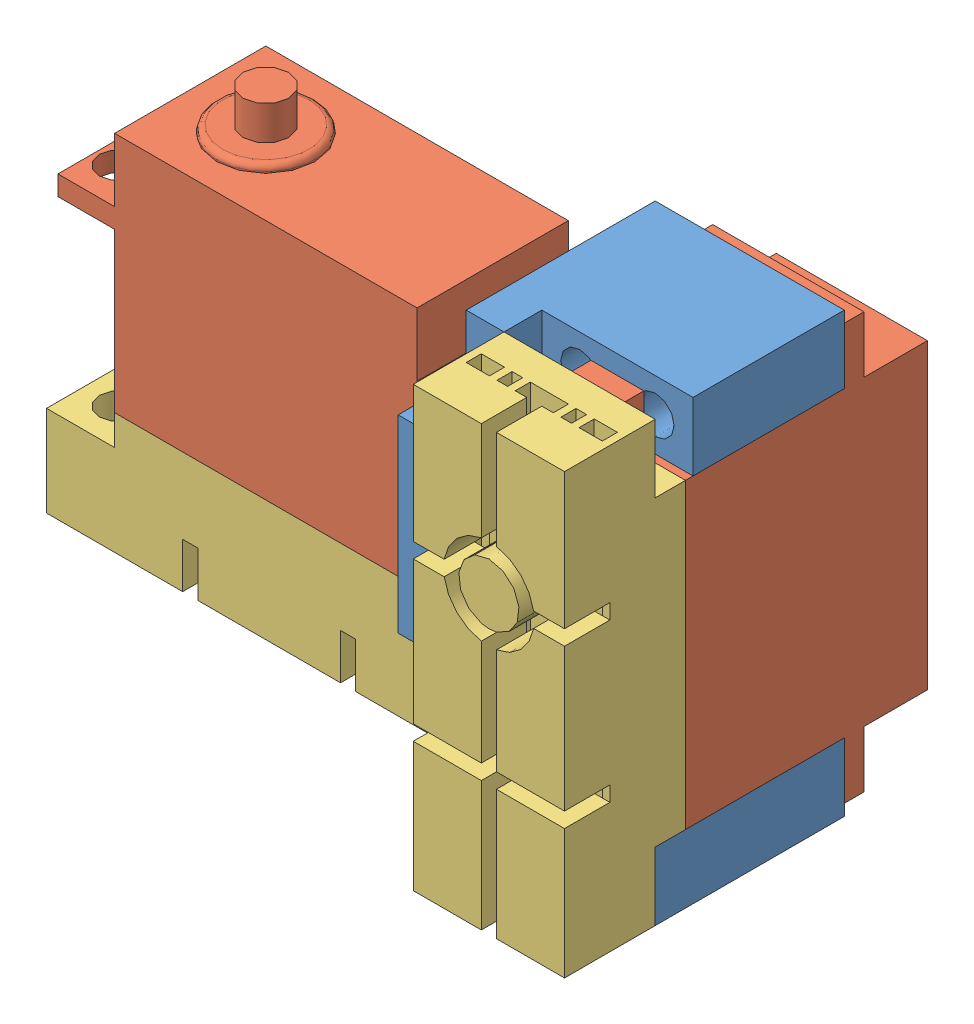
SolidWorks assembly Pate, configuration Défaut. Lengths in mm.
Overall size (83 58 53.5).
5 component instances, 3 part files, 14 mates.
Components (placement in the parent):
- shoulder-1: shoulder [Défaut] at origin size (34 58 25)
- Servo_TGY1501_body-1: Servo_TGY1501_body [Défaut] at (0 -8.5 12.5) x (-1 0 0) z (0 0 -1) size (55 41 20)
- base_servo-1: base_servo [Défaut] at (-49 -12.5 2.5) x (1 0 0) z (0 -1 0) size (58 20 16)
- Servo_TGY1501_body-2: Servo_TGY1501_body [Défaut] at (24 -20 21) x (0 1 0) z (-1 0 0) size (55 41 20)
- base_servo-2: base_servo [Défaut] at (14 29 25) x (0 -1 0) z (0 0 1) size (58 20 16)
Mates (geometry in assembly coordinates):
- Parallèle1: parallel anti-aligned: plane of Servo_TGY1501_body-1 through (0 -8.5 2.5) normal (0 -1 0); plane of base_servo-1 through (-49 -12.5 2.5) normal (0 1 0)
- Coaxiale1: concentric anti-aligned: cylinder of Servo_TGY1501_body-1; cylinder of base_servo-1
- Coaxiale2: concentric aligned: cylinder of Servo_TGY1501_body-1; cylinder of base_servo-1
- Coïncidente2: coincident anti-aligned: plane of Servo_TGY1501_body-1 through (0 -8.5 2.5) normal (0 -1 0); plane of base_servo-1 through (0 -8.5 2.5) normal (0 1 0)
- Coïncidente3: coincident anti-aligned: plane of shoulder-1 through (0 12.5 25) normal (0 1 0); plane of Servo_TGY1501_body-1 through (-40 12.5 30.4379) normal (0 -1 0)
- Coaxiale3: concentric aligned: cylinder of shoulder-1; cylinder of Servo_TGY1501_body-1
- Coaxiale4: concentric anti-aligned: cylinder of shoulder-1; cylinder of base_servo-1
- Parallèle2: parallel anti-aligned: plane of Servo_TGY1501_body-2 through (14 -20 21) normal (0 0 1); plane of base_servo-2 through (14 29 25) normal (0 0 -1)
- Coïncidente5: coincident aligned: plane of Servo_TGY1501_body-2 through (34 -20 21) normal (1 0 0); plane of base_servo-2 through (34 29 31) normal (1 0 0)
- Coïncidente6: coincident aligned: plane of Servo_TGY1501_body-2 through (14 -20 -11) normal (0 -1 0); plane of base_servo-2 through (34 -20 21) normal (0 -1 0)
- Coïncidente7: coincident anti-aligned: plane of Servo_TGY1501_body-2 through (14 -20 21) normal (0 0 1); plane of base_servo-2 through (14 -20 21) normal (0 0 -1)
- Coïncidente8: coincident anti-aligned: plane of shoulder-1 through (9 12.5 25) normal (0 0 1); plane of base_servo-2 through (14 29 25) normal (0 0 -1)
- Coïncidente9: coincident anti-aligned: plane of shoulder-1 through (14 20 25) normal (1 0 0); plane of Servo_TGY1501_body-2 through (14 -20 21) normal (-1 0 0)
- Coïncidente10: coincident anti-aligned: plane of shoulder-1 through (34 -20 25) normal (0 1 0); plane of Servo_TGY1501_body-2 through (14 -20 -11) normal (0 -1 0)
